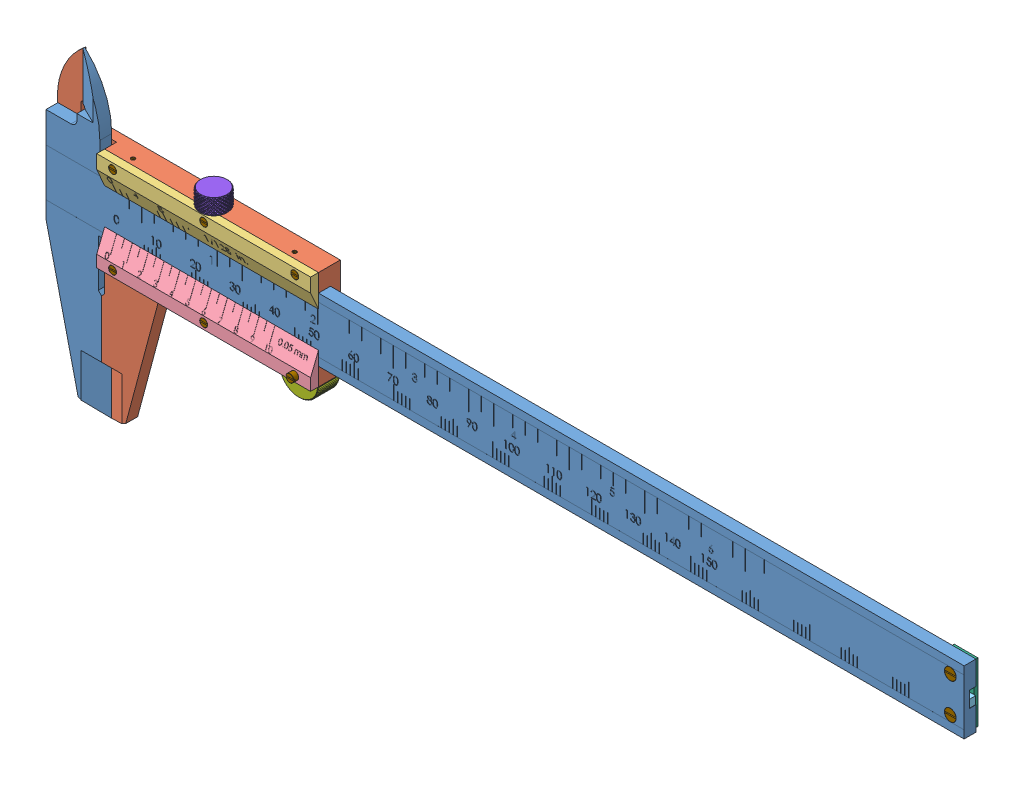
SolidWorks assembly Złożenie1, configuration Domyślna. Lengths in mm.
Overall size (231.95 77.25 8.76).
18 component instances, 9 part files, 46 mates.
Components (placement in the parent):
- Skala1-1: Skala1 [Default] at (114.4175 27.9872 231.8325) size (231.83 77.25 3)
- Skala2-1: Skala2 [Default] at (-48.6055 27.9872 230.5825) size (68.93 77.19 5.5)
- Cale-1: Cale [Default] at (-75.6055 36.4872 234.3325) size (54 8 2)
- MM-1: MM [Default] at (-75.6055 19.4872 233.3325) x (-1 0 0) z (0 0 1) size (54 8 2)
- Szpikulec-1: Szpikulec [Default] at (-90.6055 28.0122 231.1825) x (0 0 -1) z (1 0 0) size (1.6 3.95 205)
- Płytka-1: Płytka [Default] at (110.9175 27.9872 229.3325) x (0 -1 0) z (0 0 1) size (15 6 1)
- Przycisk-1: Przycisk [Default] at (-53.6055 15.4872 233.3325) x (1 0 0) z (0 0 -1) size (10 4.97 5.5)
- Śruba1-1: Śruba1 [Default] at (-76.5455 33.9872 231.8325) x (0.99973 0 0.02325) z (-0.02325 0 0.99973) size (7.02 10.5 7.01)
- Śruba2-1: Śruba2 [M1x4.75] at (-96.9455 40.4872 231.8325) x (0 0 -1) z (-1 0 0) size (1 4.75 1)
- Śruba2-2: Śruba2 [M1x4.75] at (-56.1455 40.4872 231.8325) x (0 0 1) z (1 0 0) size (1 4.75 1)
- Śruba2-3: Śruba2 [M1x1.25] at (-98.6055 38.9872 235.3325) x (0 -1 0) z (1 0 0) size (2 2.5 2)
- Śruba2-4: Śruba2 [M1x1.25] at (-75.6055 16.9872 235.3325) x (0 -1 0) z (1 0 0) size (2 2.5 2)
- Śruba2-5: Śruba2 [M1x1.25] at (-75.6055 38.9872 235.3325) x (0 -1 0) z (1 0 0) size (2 2.5 2)
- Śruba2-6: Śruba2 [M1x1.25] at (-98.6055 16.9872 235.3325) x (0 -1 0) z (1 0 0) size (2 2.5 2)
- Śruba2-7: Śruba2 [M1x1.25] at (-52.6055 16.9872 236.5969) x (0 -1 0) z (1 0 0) size (2 2.5 2)
- Śruba2-8: Śruba2 [M1x1.25] at (-52.6055 38.9872 235.3325) x (0 1 0) z (-1 0 0) size (2 2.5 2)
- Śruba2-9: Śruba2 [M2x2.5] at (110.9175 23.4872 233.3325) x (0 -1 0) z (1 0 0) size (3 4 3)
- Śruba2-10: Śruba2 [M2x2.5] at (110.9175 32.4872 233.3325) x (0 -1 0) z (1 0 0) size (3 4 3)
Mates (geometry in assembly coordinates):
- Wspólnie1: coincident anti-aligned: plane of Skala1-1 through (-103.3155 35.7372 230.3325) normal (0 0 -1); plane of Skala2-1 through (-48.6055 27.9872 230.3325) normal (0 0 1)
- Wspólnie2: coincident anti-aligned: plane of Skala1-1 through (114.4175 35.9872 233.3325) normal (0 1 0); plane of Skala2-1 through (-48.6055 35.9872 230.3325) normal (0 -1 0)
- Limit odległości1: limit distance = 0.01 mm anti-aligned: plane of Skala1-1 through (-103.4155 -20.0128 233.3325) normal (1 0 0); plane of Skala2-1 through (-103.4055 -20.0128 233.3325) normal (-1 0 0)
- Wspólnie4: coincident aligned: circle of Skala2-1; circle of Cale-1
- Wspólnie5: coincident aligned: circle of Skala2-1; circle of Cale-1
- Wspólnie6: coincident aligned: circle of Skala2-1; circle of MM-1
- Wspólnie7: coincident aligned: circle of Skala2-1; circle of MM-1
- Wspólnie8: coincident anti-aligned: plane of Skala1-1 through (-95.5825 29.9872 231.9825) normal (0 0 -1); plane of Szpikulec-1 through (114.3945 26.0372 231.9825) normal (0 0 1)
- Wspólnie9: coincident anti-aligned: plane of Skala1-1 through (-95.5825 29.9872 230.3325) normal (0 -1 0); plane of Szpikulec-1 through (114.3945 29.9872 231.9825) normal (0 1 0)
- Odległość2: distance = 163 mm aligned: plane of Szpikulec-1 through (114.3945 28.0122 231.1825) normal (1 0 0); plane of Skala2-1 through (-48.6055 27.9872 233.3325) normal (1 0 0)
- Wspólnie11: coincident anti-aligned: circle of Skala1-1; circle of Płytka-1
- Wspólnie12: coincident anti-aligned: circle of Skala1-1; circle of Płytka-1
- Wspólnie13: coincident aligned: line of Skala2-1 through (-102.6055 15.4872 227.8325) axis (1 0 0); line of Przycisk-1 through (-58.3555 15.4872 227.8325) axis (1 0 0)
- Wspólnie14: coincident anti-aligned: line of Skala2-1 through (-48.6055 15.4872 233.3325) axis (0 0 -1); line of Przycisk-1 through (-48.6055 15.4872 228.0825) axis (0 0 1)
- Koncentryczne1: concentric anti-aligned: cylinder of Skala2-1 through (-76.5455 -20.0138 231.8325) axis (0 1 0) radius 1; cylinder of Śruba1-1 through (-76.5455 40.4872 231.8325) axis (0 -1 0) radius 1
- Wspólnie15: coincident anti-aligned: plane of Skala2-1 through (-48.6055 40.4872 233.3325) normal (0 1 0); plane of Śruba1-1 through (-76.5455 40.4872 231.8325) normal (0 -1 0)
- Koncentryczne2: concentric aligned: cylinder of Skala2-1 through (-96.9455 37.4872 231.8325) axis (0 1 0) radius 0.5; cylinder of Śruba2-1 through (-96.9455 38.4872 231.8325) axis (0 1 0) radius 0.5
- Wspólnie16: coincident aligned: plane of Skala2-1 through (-48.6055 40.4872 233.3325) normal (0 1 0); plane of Śruba2-1 through (-96.9455 40.4872 231.8325) normal (0 1 0)
- Koncentryczne3: concentric aligned: cylinder of Skala2-1 through (-56.1455 37.4872 231.8325) axis (0 1 0) radius 0.5; cylinder of Śruba2-2 through (-56.1455 38.4872 231.8325) axis (0 1 0) radius 0.5
- Wspólnie17: coincident aligned: plane of Skala2-1 through (-48.6055 40.4872 233.3325) normal (0 1 0); plane of Śruba2-2 through (-56.1455 40.4872 231.8325) normal (0 1 0)
- Koncentryczne4: concentric anti-aligned: circle of MM-1; circle of Śruba2-6
- Koncentryczne5: concentric anti-aligned: circle of Cale-1; circle of Śruba2-3
- Koncentryczne6: concentric anti-aligned: circle of MM-1; circle of Śruba2-4
- Koncentryczne7: concentric anti-aligned: circle of MM-1; circle of Śruba2-7
- Koncentryczne8: concentric anti-aligned: circle of Cale-1; circle of Śruba2-8
- Koncentryczne9: concentric anti-aligned: circle of Cale-1; circle of Śruba2-5
- Wspólnie24: coincident aligned: plane of MM-1 through (-75.6055 19.4872 235.3325) normal (0 0 1); plane of Śruba2-6 through (-98.6055 16.9872 235.3325) normal (0 0 1)
- Wspólnie25: coincident aligned: plane of MM-1 through (-75.6055 19.4872 235.3325) normal (0 0 1); plane of Śruba2-4 through (-75.6055 16.9872 235.3325) normal (0 0 1)
- Wspólnie26: coincident aligned: plane of Cale-1 through (-75.6055 36.4872 235.3325) normal (0 0 1); plane of Śruba2-3 through (-98.6055 38.9872 235.3325) normal (0 0 1)
- Wspólnie27: coincident aligned: plane of Cale-1 through (-75.6055 36.4872 235.3325) normal (0 0 1); plane of Śruba2-5 through (-75.6055 38.9872 235.3325) normal (0 0 1)
- Wspólnie28: coincident aligned: plane of Cale-1 through (-75.6055 36.4872 235.3325) normal (0 0 1); plane of Śruba2-8 through (-52.6055 38.9872 235.3325) normal (0 0 1)
- Równolegle5: parallel aligned: line of Cale-1 through (-102.6055 36.9793 235.3325) axis (1 0 0); line of Śruba2-5 through (-76.5942 39.1372 234.9825) axis (1 0 0)
- Równolegle6: parallel aligned: line of Cale-1 through (-102.6055 36.9793 235.3325) axis (1 0 0); line of Śruba2-3 through (-99.5942 39.1372 234.9825) axis (1 0 0)
- Równolegle7: parallel aligned: line of MM-1 through (-102.6055 15.4872 235.3325) axis (1 0 0); line of Śruba2-6 through (-99.5436 17.1372 235.3325) axis (1 0 0)
- Równolegle8: parallel anti-aligned: line of MM-1 through (-48.6055 18.4872 235.3325) axis (-1 0 0); line of Śruba2-4 through (-76.5436 16.8372 235.3325) axis (1 0 0)
- Równolegle9: parallel anti-aligned: line of MM-1 through (-48.6055 18.4872 235.3325) axis (-1 0 0); line of Śruba2-7 through (-53.5436 17.1372 236.5969) axis (1 0 0)
- Równolegle10: parallel anti-aligned: line of Cale-1 through (-102.6055 36.9793 235.3325) axis (1 0 0); line of Śruba2-8 through (-51.6674 39.1372 235.3325) axis (-1 0 0)
- Równolegle11: parallel: line of Śruba2-1 through (-96.5212 40.4872 231.9825) axis (-1 0 0); plane of Śruba2-5 through (-75.6055 38.9872 235.3325) normal (0 0 1)
- Równolegle12: parallel anti-aligned: line of Skala2-1 through (-48.6055 40.4872 233.3325) axis (-1 0 0); line of Śruba2-2 through (-56.6224 40.1372 231.9825) axis (1 0 0)
- Koncentryczne10: concentric anti-aligned: circle of Skala1-1; circle of Śruba2-9
- Koncentryczne11: concentric anti-aligned: circle of Skala1-1; circle of Śruba2-10
- Wspólnie29: coincident aligned: plane of Skala1-1 through (-103.3155 35.7372 233.3325) normal (0 0 1); plane of Śruba2-10 through (110.9175 32.4872 233.3325) normal (0 0 1)
- Wspólnie30: coincident aligned: plane of Skala1-1 through (-103.3155 35.7372 233.3325) normal (0 0 1); plane of Śruba2-9 through (110.9175 23.4872 233.3325) normal (0 0 1)
- Równolegle13: parallel aligned: line of Skala1-1 through (-96.7825 19.9872 233.3335) axis (1 0 0); line of Śruba2-9 through (109.4753 23.3372 233.3325) axis (1 0 0)
- Równolegle14: parallel: plane of Skala1-1 through (114.4175 27.9872 233.3335) normal (0 0 1); line of Śruba2-10 through (109.4251 32.3372 232.9825) axis (1 0 0)
- Równolegle16: parallel aligned: line of Skala1-1 through (65.5345 33.9872 233.3325) axis (1 0 0); line of Śruba2-10 through (109.4753 32.6372 233.3325) axis (1 0 0)
